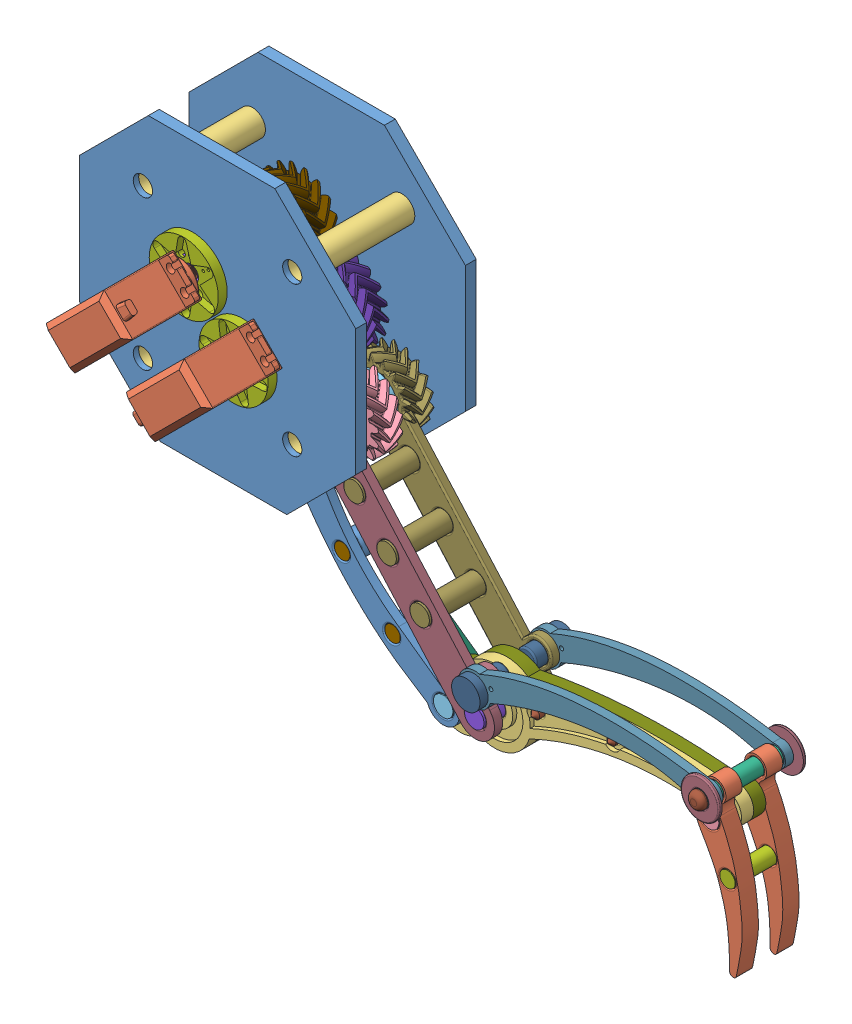
SolidWorks assembly Mecha, configuration Default. Lengths in mm.
Overall size (1060.22 951 137.35).
60 component instances, 32 part files, 3 mates.
Components (placement in the parent):
- MechaGodzilla-1: MechaGodzilla [Default] at (320.8443 -153.3244 456.232) size (975 951 0)
- HipGearBoxv02v1-1: HipGearBoxv02v1 [Default] at (1131.4907 441.7995 540.966) x (-0.707107 -0.707107 0) z (0 0 -1) size (182.27 362.96 1100.61) (flexible)
  - GearBoxBackPlatev02-1: GearBoxBackPlatev02 [Default] at origin size (136.08 144.44 5.33)
  - MG995R Dogv00-1: MG995R Dogv00 [Default] at (-10.5654 34.675 -27.3658) x (-1 0 0) z (0 1 0) size (54.05 45.33 20.04)
  - MG995R Dogv00-2: MG995R Dogv00 [Default] at (10.5654 34.675 -27.3658) x (1 0 0) z (0 -1 0) size (54.05 45.33 20.04) (hidden)
  - GearAxelv01-1: GearAxelv01 [Default] at (0 0 2.667) x (0.951994 -0.306118 0) z (0 0 1) size (12.7 12.7 54)
  - GearAxelv01-2: GearAxelv01 [Default] at (-52.0125 52.0125 2.667) size (12.7 12.7 54)
  - GearAxelv01-3: GearAxelv01 [Default] at (0 104.025 2.667) size (12.7 12.7 54)
  - GearAxelv01-4: GearAxelv01 [Default] at (52.0125 52.0125 2.667) size (12.7 12.7 54)
  - QuadDHGv02-1: QuadDHGv02 [PreviewCfg] at (0 0 29.667) x (0 0 -1) z (0.605947 0.795505 0) size (55.25 53.37 49.37)
  - HexShaftv02-1: HexShaftv02 [Default] at (0 0 29.667) x (0.549636 -0.835404 0) z (0 0 1) size (22 22 48)
  - HexShaftThighDrivev02-1: HexShaftThighDrivev02 [Default] at (0 69.35 29.6) x (-0.310664 -0.95052 0) z (0 0 1) size (22 22 48)
  - HornAdapterCap04-2: HornAdapterCap04 [Default] at (0 34.675 63.734) x (0.09916 0.995071 0) z (0 0 -1) size (34 34 10)
  - HornAdapterCapCuppler04-2: HornAdapterCapCuppler04 [Default] at (0 34.675 62.6176) x (-0.09916 -0.995071 0) z (0 0 -1) size (13.84 13.51 14.72)
  - HexShaftQuadDrive-1: HexShaftQuadDrive [Default] at (0 34.675 29.6) x (-0.41166 0.911337 0) z (0 0 1) size (19.05 22 48)
  - HornAdapterCap04-3: HornAdapterCap04 [Default] at (0 34.675 -4.4) x (0.911337 0.41166 0) z (0 0 1) size (34 34 10)
  - HornAdapterCapCuppler04-3: HornAdapterCapCuppler04 [Default] at (0 34.675 -3.2836) x (0.911337 0.41166 0) z (0 0 1) size (13.84 13.51 14.72)
  - HexShaftQuadDriveSpacerv02-1: HexShaftQuadDriveSpacerv02 [Default] at (0 34.675 13) x (-0.583411 -0.812177 0) z (0 0 1) size (28 28 14.8)
  - HexDriveQuadDHGv02-2: HexDriveQuadDHGv02 [PreviewCfg] at (0 34.675 29.667) x (0 0 1) z (0.995071 -0.09916 0) size (53.45 53.37 46.68)
  - HornAdapterCap04-4: HornAdapterCap04 [Default] at (0 69.35 -4.4) x (-0.206217 0.978506 0) z (0 0 1) size (34 34 10)
  - HornAdapterCapCuppler04-4: HornAdapterCapCuppler04 [Default] at (0 69.35 -3.2836) x (-0.206217 0.978506 0) z (0 0 1) size (13.84 13.51 14.72)
  - OuterThigh_DHG001-1: OuterThigh_DHG001 [PreviewCfg] at (0 0 47.067) x (0 0 -1) z (0.998299 0.058296 0) size (50.53 157.97 46.68)
  - InnerThigh_DHG002-1: InnerThigh_DHG002 [PreviewCfg] at (0 0 12.267) x (0 0 -1) z (0.998299 0.058296 0) size (50.45 157.97 46.68)
  - HornAdapterCap04-5: HornAdapterCap04 [Default] at (0 69.35 63.734) x (-0.206217 0.978506 0) z (0 0 -1) size (34 34 10)
  - HornAdapterCapCuppler04-5: HornAdapterCapCuppler04 [Default] at (0 69.35 62.6176) x (-0.206217 0.978506 0) z (0 0 -1) size (13.84 13.51 14.72)
  - RearCalf001-1: RearCalf001 [Default] at (-94.3315 -177.8908 47.067) x (-0.571767 0.820416 0) z (0 0 -1) size (30.5 126.28 4)
  - RearQuadsOutsidev02-2: RearQuadsOutsidev02 [Default] at (16.6825 -5.7792 38.067) x (-0.994263 -0.106958 0) z (0 0 -1) size (28.65 131.48 10.4)
  - RearShinOuterv02-2: RearShinOuterv02 [Default] at (6.6594 -114.0389 32.667) x (-0.94074 -0.33913 0) z (0 0 1) size (147.48 62.43 6)
  - DHGIdlerv02-1: DHGIdlerv02 [PreviewCfg] at (0 34.675 12.267) x (0 0 1) z (0.978481 -0.206337 0) size (50.45 53.37 46.68)
  - DHGhexSidesv02-2: DHGhexSidesv02 [PreviewCfg] at (0 69.35 12.267) x (0 0 -1) z (-0.978506 -0.206217 0) size (50.45 53.37 46.68)
  - GearBoxBackPlatev02-2: GearBoxBackPlatev02 [Default] at (0 0 59.334) x (-1 0 0) z (0 0 -1) size (136.08 144.44 5.33)
  - DHGIdlerv02-2: DHGIdlerv02 [PreviewCfg] at (0 34.675 47.067) x (0 0 1) z (0.978481 -0.206337 0) size (50.45 53.37 46.68)
  - DHGhexSidesv02-3: DHGhexSidesv02 [PreviewCfg] at (0 69.35 47.067) x (0 0 -1) z (-0.978506 -0.206217 0) size (50.45 53.37 46.68)
  - HexShaftQuadDriveSpacerv02-3: HexShaftQuadDriveSpacerv02 [Default] at (0 34.675 46.334) x (-0.41166 0.911337 0) z (0 0 -1) size (28 28 14.8)
  - RearQuadsInsidev02-2: RearQuadsInsidev02 [Default] at (16.6825 -5.7792 21.267) x (-0.994263 -0.106958 0) z (0 0 -1) size (28.65 131.48 10.4)
  - RearFootv02-1: RearFootv02 [Default] at (-83.0353 -185.0753 39.667) x (-0.901871 0.432005 0) z (0 0 -1) size (73.59 40.54 8)
  - RearShinInnerv02-2: RearShinInnerv02 [Default] at (6.6594 -114.0389 26.667) x (-0.94074 -0.33913 0) z (0 0 1) size (147.48 62.43 6)
  - RearFootv02-2: RearFootv02 [Default] at (-83.0353 -185.0753 19.667) x (-0.901871 0.432005 0) z (0 0 -1) size (73.59 40.54 8)
  - RearCalf001-2: RearCalf001 [Default] at (-94.3315 -177.8908 12.267) x (-0.571767 0.820416 0) z (0 0 -1) size (30.5 126.28 4)
  - FootShinPivotv02-1: FootShinPivotv02 [Default] at (-83.0353 -185.0753 29.667) size (9.6 9.6 28)
  - QuadShinPivotv02-1: QuadShinPivotv02 [Default] at (27.3783 -105.2056 29.667) size (9.6 9.6 20.8)
  - FootCalfPivotv02-1: FootCalfPivotv02 [Default] at (-94.3315 -177.8908 29.667) size (7.6 7.6 40)
  - FootFootBridgev02-1: FootFootBridgev02 [Default] at (-74.0544 -206.8692 29.667) size (7.6 7.6 28)
  - ThighShinPivotv02-2: ThighShinPivotv02 [Default] at (6.6594 -114.0389 29.667) size (9.6 9.6 32)
  - QuadQuadBridgev02-1: QuadQuadBridgev02 [Default] at (32.4687 -74.4862 29.667) size (7.6 7.6 20)
  - QuadQuadBridgev02-2: QuadQuadBridgev02 [Default] at (33.8615 -40.8148 29.667) size (7.6 7.6 20)
  - QuadQuadBridgev02-3: QuadQuadBridgev02 [Default] at (28.6173 -15.0712 29.667) size (7.6 7.6 20)
  - ThighCalfPivotv02-1: ThighCalfPivotv02 [Default] at (-6.9317 -105.6184 44.567) x (-1 0 0) z (0 0 -1) size (14 14 17.8)
  - ThighCalfPivotv02-2: ThighCalfPivotv02 [Default] at (-6.9317 -105.6184 14.767) size (14 14 17.8)
  - screw0_5-1: screw0_5 [Default] at (-12.3415 -123.7449 33.667) size (8.13 8.13 15.11)
  - screw0_5-2: screw0_5 [Default] at (-44.0891 -144.9624 33.667) size (8.13 8.13 15.11)
  - screw0_5-3: screw0_5 [Default] at (-71.8854 -171.5682 33.667) size (8.13 8.13 15.11)
  - ThighThighBridgev02-1: ThighThighBridgev02 [Default] at (4.3032 -73.6901 29.667) size (9.6 9.6 32)
  - ThighThighBridgev02-2: ThighThighBridgev02 [Default] at (2.8759 -49.2485 29.667) size (9.6 9.6 32)
  - ThighThighBridgev02-3: ThighThighBridgev02 [Default] at (1.4486 -24.8068 29.667) size (9.6 9.6 32)
  - screw0_5-4: screw0_5 [Default] at (-94.3315 -177.8908 51.191) x (0.984701 0.174252 0) z (0 0 1) size (8.13 8.13 15.11)
  - Washer-1: Washer [Default] at (-94.3315 -177.8908 9.667) x (-1 0 0) z (0 0 -1) size (19.05 19.05 1.52)
  - screw0_5-5: screw0_5 [Default] at (-94.3315 -177.8908 8.143) x (-1 0 0) z (0 0 -1) size (8.13 8.13 15.11)
  - Washer-2: Washer [Default] at (-94.3315 -177.8908 49.667) size (19.05 19.05 1.52)
  - MG995R Dogv00-3: MG995R Dogv00 [Default] at (10.5654 69.35 -27.3658) x (1 0 0) z (0 -1 0) size (54.05 45.33 20.04)
Mates (geometry in assembly coordinates):
- Concentric1: concentric aligned: circle of MechaGodzilla-1; cylinder of HipGearBoxv02v1-1/GearAxelv01-3 through (1057.934 515.3563 484.299) axis (0 0 1) radius 5.334
- Concentric2: concentric aligned: circle of MechaGodzilla-1; cylinder of HipGearBoxv02v1-1/GearAxelv01-2 through (1131.4907 515.3563 484.299) axis (0 0 1) radius 5.334
- Distance1: distance = 25.4 mm anti-aligned: plane of HipGearBoxv02v1-1/GearBoxBackPlatev02-2 through (1131.4907 441.7995 481.632) normal (0 0 -1); plane of MechaGodzilla-1 through (320.8443 -153.3244 456.232) normal (0 0 1)
